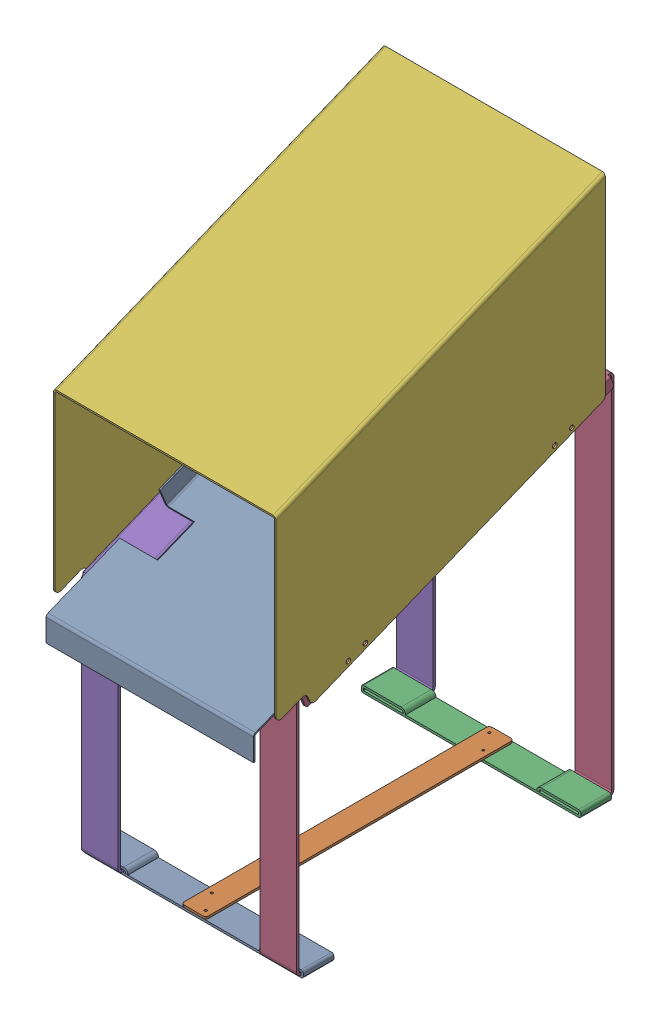
SolidWorks assembly GE-15004_ASM, configuration Default. Lengths in mm.
Overall size (463.55 1141.84 780.07).
7 component instances, 5 part files, 0 mates.
Components (placement in the parent):
- GE-15005-1: GE-15005 [Default] at origin size (457.2 14.29 63.5)
- GE-15006-1: GE-15006 [Default] at (0 0 -288.925) size (50.8 4.62 641.35)
- GE-15005-2: GE-15005 [Default] at (0 0 -577.85) size (457.2 14.29 63.5)
- GE-15007-1: GE-15007 [Default] at (185.8772 0 40.9905) x (1 0 0) z (0 -1 0) size (85.44 660.4 764.01)
- GE-15007-2: GE-15007 [Default] at (-185.8772 0 40.9905) x (1 0 0) z (0 -1 0) size (85.44 660.4 764.01)
- GE-15008-1: GE-15008 [Default] at (0.2819 619.9194 -243.2609) x (1 0 0) z (0 -0.374607 0.927184) size (431.8 86.39 806.43)
- GE-15009-1: GE-15009 [Default] at (-0.0025 453.7355 91.7786) x (1 0 0) z (0 -1 0) size (463.55 685.8 650.75)
